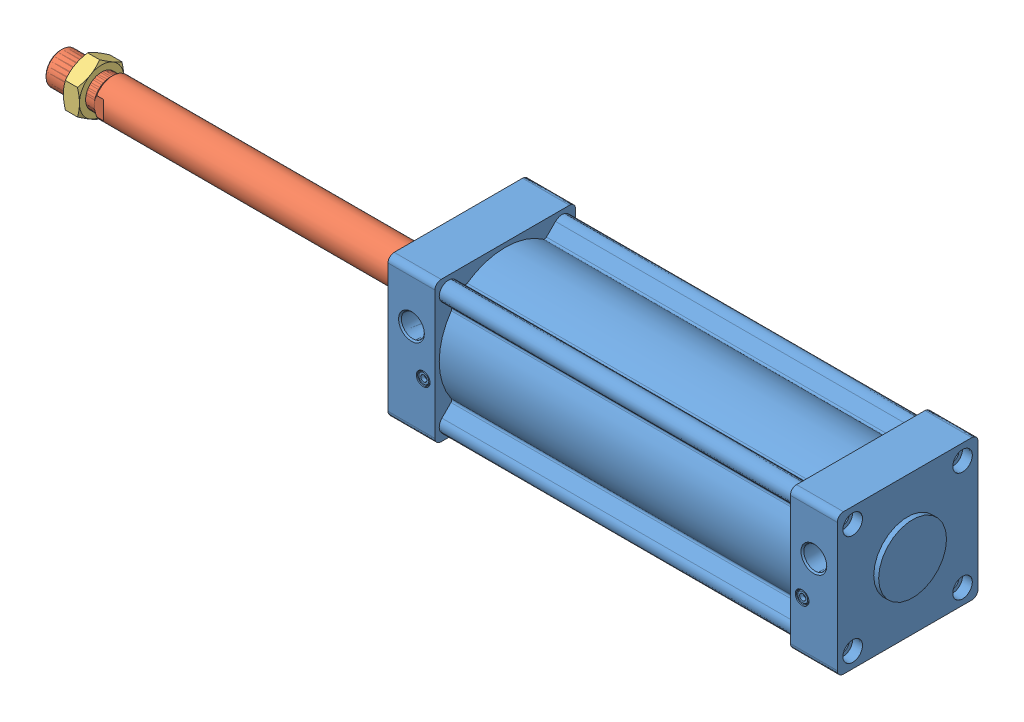
SolidWorks assembly JSI100x250S(000)+(), configuration 默认. Lengths in mm.
Overall size (690 114 114).
3 component instances, 3 part files, 6 mates.
Components (placement in the parent):
- JSI-100x250-S- (0) c-1: JSI-100x250-S- (0) c [默认] at origin size (388 114 114)
- JSI JSID JSIJ POLE 100JSI2500-1: JSI JSID JSIJ POLE 100JSI2500 [默认] at (-270 0 0) x (0 0 -1) z (-1 0 0) size (99 99 401)
- JSI-100-M26x1_5 - Nut-1: JSI-100-M26x1_5 - Nut [默认] at (-302 0 0) size (13 41.57 36)
Mates (geometry in assembly coordinates):
- 重合1: coincident anti-aligned: line of JSI-100x250-S- (0) c-1 through (161.8 -80.9 0) axis (0 1 0); line of JSI JSID JSIJ POLE 100JSI2500-1 through (161.8 -189.1 0) axis (0 -1 0)
- 角度3: planar angle = 0 rad aligned: plane of JSI JSID JSIJ POLE 100JSI2500-1; plane of JSI-100x250-S- (0) c-1 through (0 0 0) normal (0 0 -1)
- 重合2: coincident anti-aligned: line of JSI JSID JSIJ POLE 100JSI2500-1 through (161.8 -350.9 0) axis (0 1 0); line of JSI-100-M26x1_5 - Nut-1 through (161.8 -221.1 0) axis (0 -1 0)
- 角度6: planar angle = 0 rad aligned: plane of JSI-100-M26x1_5 - Nut-1 through (-302 0 0) normal (0 0 -1); plane of JSI JSID JSIJ POLE 100JSI2500-1
- LimitDistance1: limit distance = 322 mm aligned: plane of JSI JSID JSIJ POLE 100JSI2500-1 through (-322 0 0) normal (-1 0 0); plane of JSI-100x250-S- (0) c-1 through (0 -52 52) normal (-1 0 0)
- 距离2: distance = 20 mm aligned: plane of JSI-100-M26x1_5 - Nut-1 through (-302 0 0) normal (-1 0 0); plane of JSI JSID JSIJ POLE 100JSI2500-1 through (-322 0 0) normal (-1 0 0)
